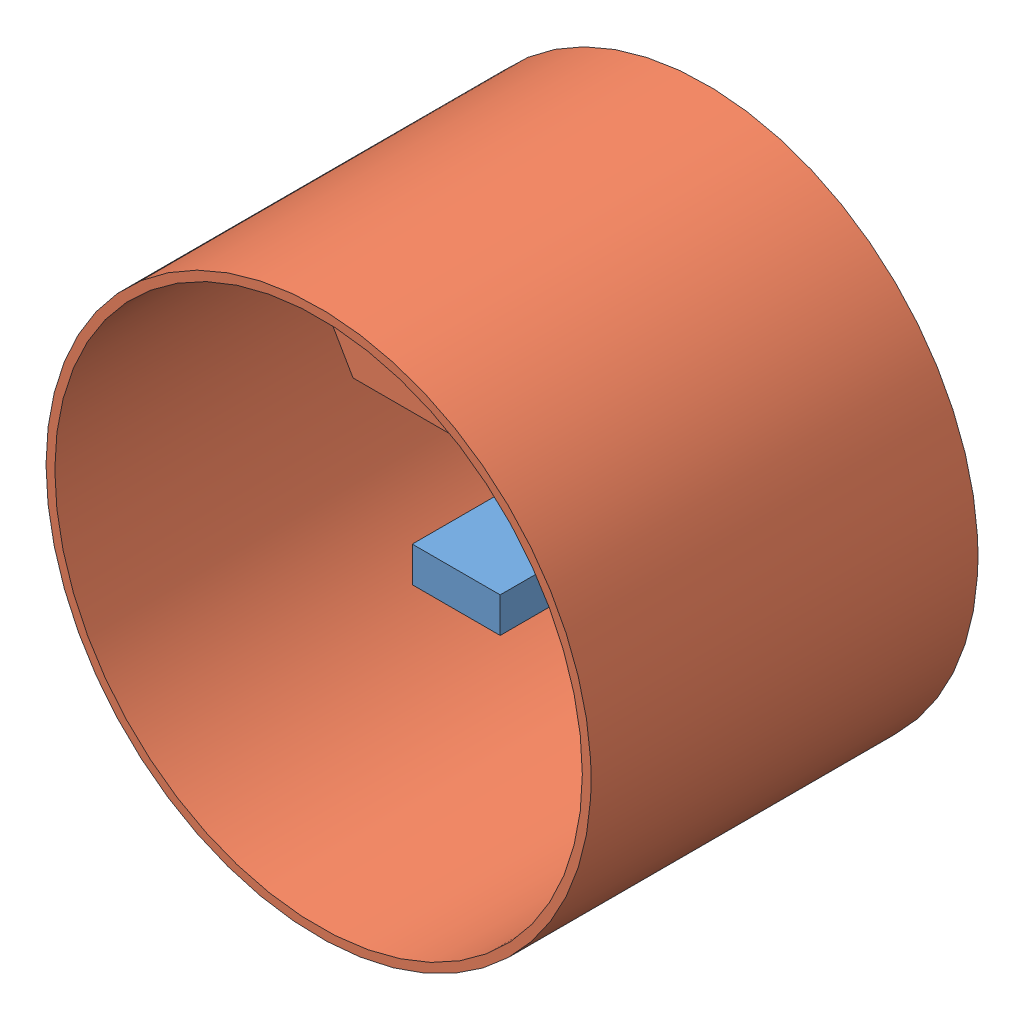
SolidWorks assembly gantry+bed, configuration Default. Lengths in mm.
Overall size (310 310 298.69).
2 component instances, 2 part files, 0 mates.
Components (placement in the parent):
- 治疗床-2: 治疗床 [默认] at (37.3241 102.2609 27.1081) size (50 20 200)
- gantry模型-2: gantry模型 [默认] at (82.7316 155.9444 215.7965) size (310 310 220)
